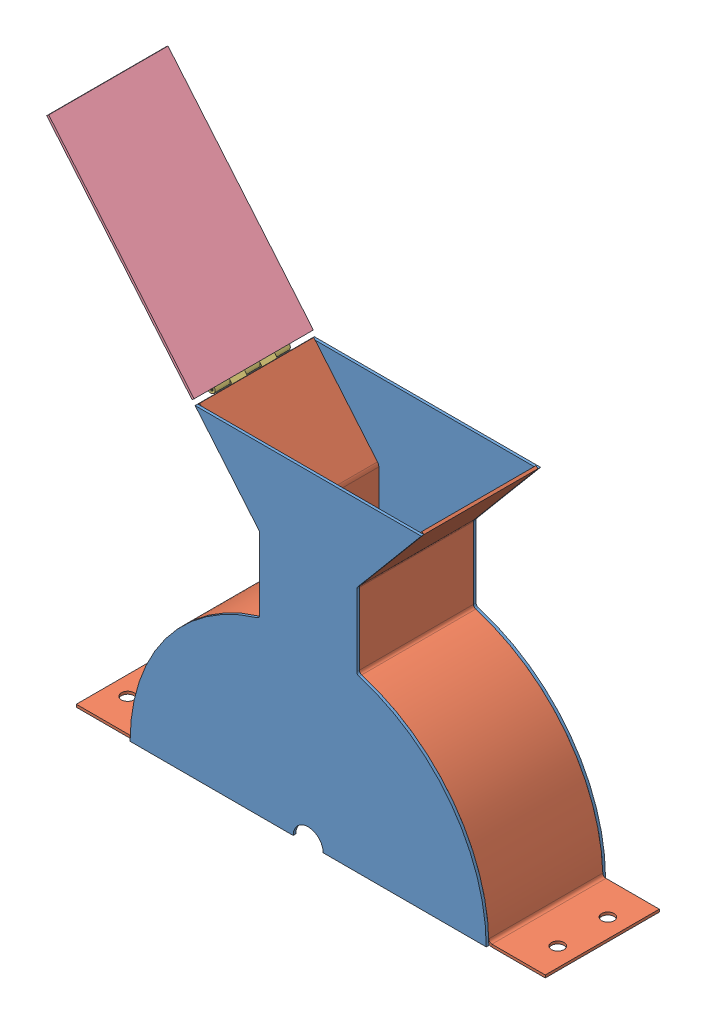
SolidWorks assembly Upper Assembly Design 6, configuration Default. Lengths in mm.
Overall size (502.58 508.58 120.88).
6 component instances, 4 part files, 14 mates.
Components (placement in the parent):
- Upper Assembly - Front Face no flange-1: Upper Assembly - Front Face no flange [Default] at (130.0519 28.1852 388.305) size (360.91 327.62 2.66)
- Upper Assembly - Front Face no flange-2: Upper Assembly - Front Face no flange [Default] at (130.0519 28.1852 270.0782) size (360.91 327.62 2.66)
- Upper Assembly - Side Piece 2.0-1: Upper Assembly - Side Piece 2.0 [Default] at (130.0519 28.1852 270.0782) x (1 -0.000027 0) z (0 0 1) size (190.98 329.36 115.57)
- Upper Assembly - Side Piece 2.0-2: Upper Assembly - Side Piece 2.0 [Default] at (130.0519 28.1852 385.6482) x (-1 -0.000027 0) z (0 0 -1) size (190.98 329.36 115.57)
- Upper Assembly - Hinge-1: Upper Assembly - Hinge [16175A61] at (9.0629 356.6572 327.8632) x (-0.642788 0.766044 0) z (0 0 1) size (50.8 8.73 77.91)
- Upper Assembly - Funnel Cover-1: Upper Assembly - Funnel Cover [Default] at (12.4071 359.4634 388.305) x (-0.642788 0.766044 0) z (-0.766044 -0.642788 0) size (229.2 120.88 2.66)
Mates (geometry in assembly coordinates):
- Coincident1: coincident aligned: circle of Upper Assembly - Front Face no flange-1; circle of Upper Assembly - Side Piece 2.0-1
- Parallel1: parallel anti-aligned: line of Upper Assembly - Front Face no flange-1 through (80.7606 276.824 385.6482) axis (0 -1 0); line of Upper Assembly - Side Piece 2.0-1 through (80.7654 204.1637 385.6482) axis (0 1 0)
- Coincident3: coincident anti-aligned: circle of Upper Assembly - Front Face no flange-1; circle of Upper Assembly - Side Piece 2.0-2
- Parallel2: parallel anti-aligned: line of Upper Assembly - Front Face no flange-1 through (179.3431 204.1623 385.6482) axis (0 1 0); line of Upper Assembly - Side Piece 2.0-2 through (176.6815 276.8415 385.6482) axis (0 -1 0)
- Coincident13: coincident aligned: circle of Upper Assembly - Front Face no flange-2; circle of Upper Assembly - Side Piece 2.0-1
- Parallel6: parallel aligned: line of Upper Assembly - Front Face no flange-2 through (179.3431 204.1623 270.0782) axis (0 1 0); line of Upper Assembly - Side Piece 2.0-2 through (179.3384 204.1637 270.0782) axis (0 1 0)
- Coincident15: coincident anti-aligned: plane of Upper Assembly - Side Piece 2.0-1 through (224.1378 107.1326 270.0782) normal (-0.766044 -0.642788 0); plane of Upper Assembly - Hinge-1 through (28.7339 340.0058 365.9632) normal (0.766044 0.642788 0)
- Parallel7: parallel aligned: line of Upper Assembly - Side Piece 2.0-1 through (80.0226 278.8824 385.6482) axis (0 0 -1); line of Upper Assembly - Hinge-1 through (27.2746 338.7813 365.9632) axis (0 0 -1)
- Coincident17: coincident anti-aligned: line of Upper Assembly - Side Piece 2.0-1 through (15.4582 355.8273 270.0782) axis (0 0 1); line of Upper Assembly - Hinge-1 through (15.4582 355.8273 365.9632) axis (0 0 -1)
- Coincident18: coincident: plane of assembly; point of Upper Assembly - Side Piece 2.0-1; plane of Upper Assembly - Hinge-1 through (28.7339 340.0058 365.9632) normal (0 0 1)
- Coincident19: coincident anti-aligned: plane of Upper Assembly - Hinge-1 through (-3.9197 378.9209 365.9632) normal (0.766044 0.642788 0); plane of Upper Assembly - Funnel Cover-1 through (12.4071 359.4634 388.305) normal (-0.766044 -0.642788 0)
- Parallel8: parallel aligned: line of Upper Assembly - Hinge-1 through (-3.9197 378.9209 365.9632) axis (0 0 -1); line of Upper Assembly - Funnel Cover-1 through (12.4071 359.4634 365.9632) axis (0 0 -1)
- Coincident21: coincident aligned: line of Upper Assembly - Funnel Cover-1 through (12.4071 359.4634 365.9632) axis (0 0 -1); line of Upper Assembly - Hinge-1 through (12.4071 359.4634 335.4832) axis (0 0 -1)
- Coincident22: coincident: line of Upper Assembly - Hinge-1 through (12.4071 359.4634 365.9632) axis (-0.642788 0.766044 0)
